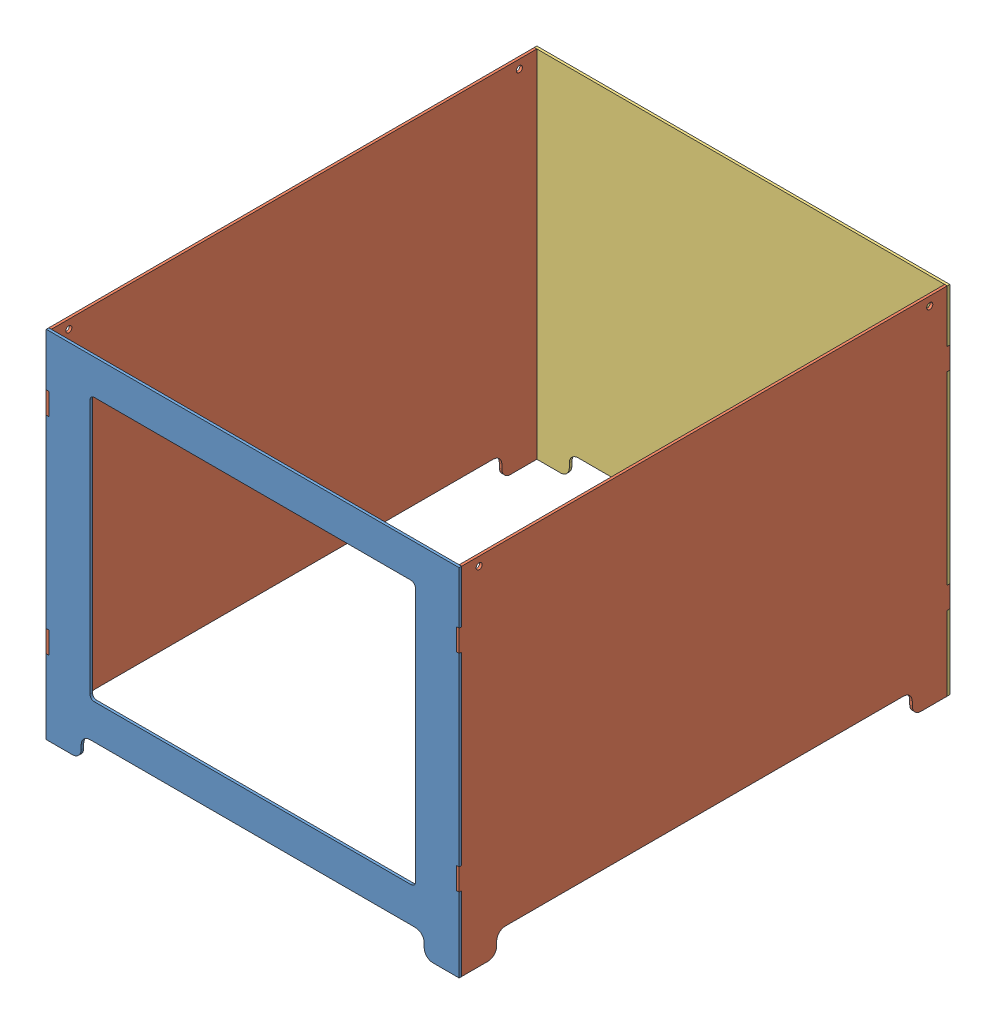
SolidWorks assembly Assem2, configuration Default. Lengths in mm.
Overall size (472.2 406.4 561.1).
4 component instances, 3 part files, 9 mates.
Components (placement in the parent):
- Front-1: Front [Default] at (23.422 2.3824 -15.428) size (472.2 406.4 2.9)
- Side-1: Side [Default] at (-212.678 2.3824 -293.078) size (2.9 406.4 561.1)
- Side-2: Side [Default] at (256.622 2.3824 -293.078) size (2.9 406.4 561.1)
- Back-1: Back [Default] at (23.422 2.3824 -573.628) size (472.2 406.4 2.9)
Mates (geometry in assembly coordinates):
- Coincident1: coincident anti-aligned: plane of Front-1 through (-182.678 -190.8176 -15.428) normal (0 0 -1); plane of Side-1 through (-209.778 145.5824 -15.428) normal (0 0 1)
- Coincident2: coincident anti-aligned: plane of Front-1 through (-209.778 145.5824 -12.528) normal (-1 0 0); plane of Side-1 through (-209.778 -190.8176 -45.428) normal (1 0 0)
- Coincident3: coincident anti-aligned: plane of Front-1 through (-212.678 145.5824 -12.528) normal (0 -1 0); plane of Side-1 through (-209.778 145.5824 -15.428) normal (0 1 0)
- Coincident4: coincident anti-aligned: plane of Side-1 through (-209.778 145.5824 -570.728) normal (0 0 -1); plane of Back-1 through (-179.778 -190.8176 -570.728) normal (0 0 1)
- Coincident5: coincident aligned: plane of Back-1 through (-212.678 145.5824 -570.728) normal (-1 0 0); plane of Side-1 through (-212.678 -190.8176 -45.428) normal (-1 0 0)
- Coincident6: coincident anti-aligned: plane of Side-1 through (-209.778 145.5824 -570.728) normal (0 1 0); plane of Back-1 through (-209.778 145.5824 -570.728) normal (0 -1 0)
- Coincident7: coincident: plane of Side-2 through (259.522 145.5824 -573.628) normal (0 0 -1); plane of Back-1 through (-182.678 -190.8176 -573.628) normal (0 0 -1)
- Coincident8: coincident: plane of Side-2 through (259.522 -190.8176 -45.428) normal (1 0 0); plane of Back-1 through (259.522 145.5824 -570.728) normal (1 0 0)
- Coincident9: coincident anti-aligned: plane of Side-2 through (259.522 145.5824 -570.728) normal (0 1 0); plane of Back-1 through (259.522 145.5824 -570.728) normal (0 -1 0)
